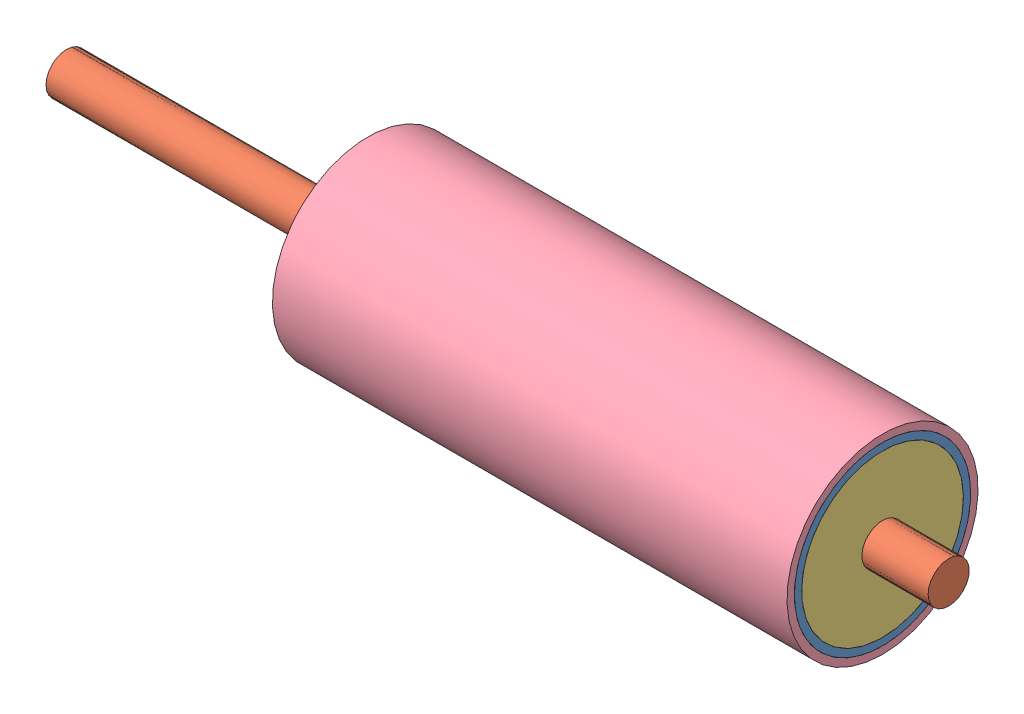
SolidWorks assembly Верхний валик_01, configuration Default. Lengths in mm.
Overall size (600 183.48 183.48).
5 component instances, 4 part files, 8 mates.
Components (placement in the parent):
- валик верхний_01-1: валик верхний_01 [Default] at (-222.5518 24.849 -31.3661) size (350 120 120)
- ось диам 10_01-1: ось диам 10_01 [Default] at (-427.5518 24.849 -31.3661) size (600 28 28)
- заглушка_01-1: заглушка_01 [Default] at (-222.5518 24.849 -31.3661) size (5 110 110)
- заглушка_01-2: заглушка_01 [Default] at (122.4482 24.849 -31.3661) x (1 0 0) z (0 0.779099 0.626901) size (5 110 110)
- силикон_01-1: силикон_01 [Default] at (-222.5518 24.849 -31.3661) x (1 0 0) z (0 -0.660801 -0.750561) size (350 130 130)
Mates (geometry in assembly coordinates):
- Концентричный1: concentric aligned: cylinder of заглушка_01-1 through (-217.5518 24.849 -31.3661) axis (-1 0 0) radius 55; cylinder of заглушка_01-2 through (127.4482 24.849 -31.3661) axis (-1 0 0) radius 55
- Концентричный2: concentric aligned: cylinder of валик верхний_01-1 through (127.4482 24.849 -31.3661) axis (-1 0 0) radius 55; cylinder of заглушка_01-1 through (-217.5518 24.849 -31.3661) axis (-1 0 0) radius 55
- Концентричный3: concentric: cylinder of ось диам 10_01-1 through (177.4482 24.849 -31.3661) axis (-1 0 0) radius 14; cylinder of заглушка_01-2 through (127.4482 24.849 -31.3661) axis (-1 0 0) radius 14
- Совпадение1: coincident aligned: plane of валик верхний_01-1 through (-222.5518 24.849 -31.3661) normal (-1 0 0); plane of заглушка_01-1 through (-222.5518 24.849 -31.3661) normal (-1 0 0)
- Совпадение2: coincident aligned: plane of валик верхний_01-1 through (127.4482 24.849 -31.3661) normal (1 0 0); plane of заглушка_01-2 through (127.4482 24.849 -31.3661) normal (1 0 0)
- Концентричный4: concentric aligned: cylinder of валик верхний_01-1 through (127.4482 24.849 -31.3661) axis (-1 0 0) radius 60; cylinder of силикон_01-1 through (127.4482 24.849 -31.3661) axis (-1 0 0) radius 60
- Совпадение4: coincident aligned: plane of валик верхний_01-1 through (127.4482 24.849 -31.3661) normal (1 0 0); plane of силикон_01-1 through (127.4482 24.849 -31.3661) normal (1 0 0)
- Расстояние1: distance = 45 mm aligned: plane of ось диам 10_01-1 through (172.4482 24.849 -31.3661) normal (1 0 0); plane of заглушка_01-2 through (127.4482 24.849 -31.3661) normal (1 0 0)
